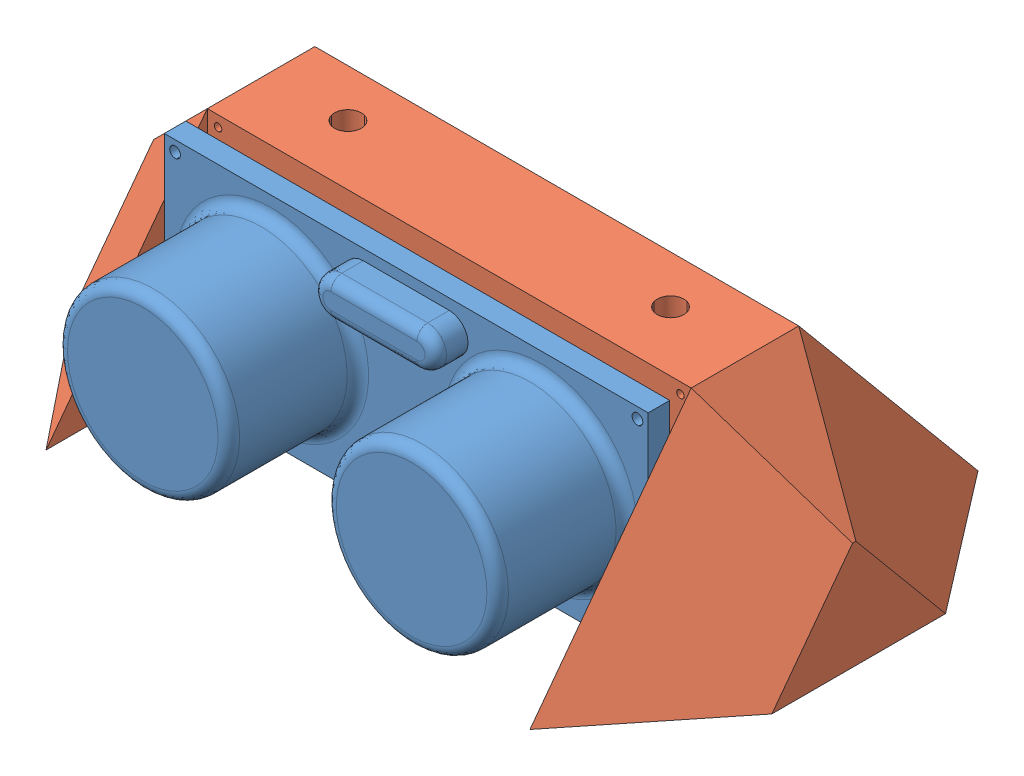
SolidWorks assembly Ultrasonico_laterales, configuration Predeterminado. Lengths in mm.
Overall size (65 25.15 42.67).
2 component instances, 2 part files, 2 mates.
Components (placement in the parent):
- sens_usonic-1: sens_usonic [Predeterminado] at (-3.1934 3.1072 40.27) size (45 25.15 18.54)
- Soporte_ultrasonico_2-1: Soporte_ultrasonico_2 [Predeterminado] at (-3.1934 3.1072 35.27) size (65 20 40.42)
Mates (geometry in assembly coordinates):
- Distancia1: distance = 2 mm anti-aligned: plane of Soporte_ultrasonico_2-1 through (-3.1934 3.1072 38.27) normal (0 0 1); plane of sens_usonic-1 through (-3.1934 3.1072 40.27) normal (0 0 -1)
- Concéntrica2: concentric aligned: circle of sens_usonic-1; circle of Soporte_ultrasonico_2-1
